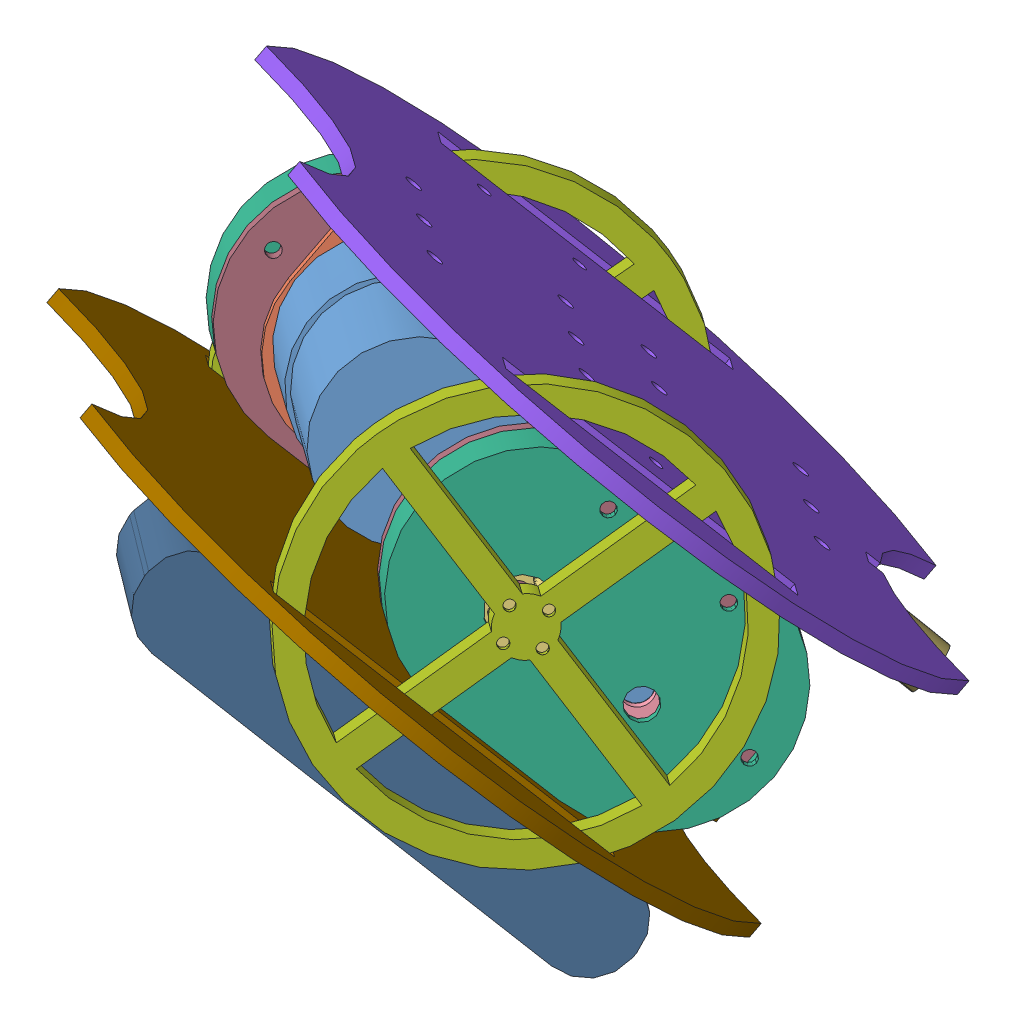
SolidWorks assembly prototype, configuration Default. Lengths in mm.
Overall size (210.36 170.64 188.11).
21 component instances, 13 part files, 47 mates.
Components (placement in the parent):
- 37D_30_1 motor-1: 37D_30_1 motor [Default] at (-25.5159 12.5017 82.0874) x (-0.250703 -0.71331 0.654474) z (-0.732412 -0.302323 -0.61006) size (36.8 36.8 74)
- 37D_30_1 motor-2: 37D_30_1 motor [Default] at (3.8647 -19.5138 58.4483) x (-0.250703 -0.71331 0.654474) z (0.732412 0.302323 0.61006) size (36.8 36.8 74)
- bracket-1: bracket [Default] at (7.9075 -5.1606 43.8592) x (-0.732412 -0.302323 -0.61006) z (-0.633025 0.632288 0.446644) size (51.2 41.6 37.6)
- bracket-3: bracket [Default] at (-19.1295 27.8223 69.4505) x (0.732412 0.302323 0.61006) z (0.633025 -0.632288 -0.446644) size (51.2 41.6 37.6)
- mod1.25_15_5mm_gear-1: mod1.25_15_5mm_gear [Default] at (28.8746 16.727 85.9165) x (0.398294 0.53646 -0.744025) z (0.732412 0.302323 0.61006) size (21.18 21.07 17)
- mod1.25_24_gear-1: mod1.25_24_gear [Default] at (22.8765 5.1631 98.8482) x (-0.593638 0.722326 0.354738) z (0.732412 0.302323 0.61006) size (32.31 32.31 2)
- 6mm_mounting_hub-1: 6mm_mounting_hub [Default] at (34.336 -11.2047 89.8723) x (0.651002 -0.048512 -0.757525) z (-0.199422 0.95197 -0.232344) size (25.4 9.2 25.4)
- 6mm_mounting_hub-2: 6mm_mounting_hub [Default] at (-59.497 -5.7937 59.8261) x (-0.524957 -0.319845 0.788745) z (-0.433581 0.897942 0.075552) size (25.4 9.2 25.4)
- gearbox_ver5-3: gearbox_ver5 [Default] at (32.0911 -0.6914 100.4708) x (-0.633025 0.632288 0.446644) z (0.732412 0.302323 0.61006) size (72.7 48 10)
- gearbox_ver5-4: gearbox_ver5 [Default] at (-57.2522 -16.307 49.2276) x (0.633025 -0.632288 -0.446644) z (-0.732412 -0.302323 -0.61006) size (72.7 48 10)
- wheel-1: wheel [Default] at (28.2216 8.343 108.8352) x (-0.552209 0.787916 0.272496) z (0.732412 0.302323 0.61006) size (80 80 5.3)
- mod1.25_15_5mm_gear-2: mod1.25_15_5mm_gear [Default] at (-33.4809 -39.4393 41.9363) x (0.544162 -0.79845 -0.257616) z (-0.732412 -0.302323 -0.61006) size (21.18 21.07 17)
- mod1.25_24_gear-2: mod1.25_24_gear [Default] at (-48.6213 2.3697 42.7749) x (0.497614 0.373868 -0.78269) z (0.732412 0.302323 0.61006) size (32.31 32.31 2)
- wheel-2: wheel [Default] at (-57.2644 -26.9437 37.6299) x (0.409219 0.520652 -0.749307) z (0.732412 0.302323 0.61006) size (80 80 5.3)
- base-2: base [Default] at (-4.8839 13.3994 54.7569) x (-0.633025 0.632288 0.446644) z (0.732412 0.302323 0.61006) size (137.46 2.9 150)
- base_2ndfloor-2: base_2ndfloor [Default] at (-17.6447 -22.9081 88.0696) x (-0.633025 0.632288 0.446644) z (0.732412 0.302323 0.61006) size (137.46 2.9 150)
- 11vbattery-1: 11vbattery [Default] at (7.0552 -15.4137 110.1303) x (-0.64782 0.625996 0.434118) z (0.719359 0.315147 0.619036) size (100 19 33)
- 7.4vbattery-1: 7.4vbattery [Default] at (-41.6591 -48.1627 75.64) x (0.647014 -0.626348 -0.434811) z (0.250703 0.71331 -0.654474) size (74 35 13)
- 1inch_spring-1: 1inch_spring [Default] at (38.6633 -36.2378 28.9452) x (-0.589271 -0.789928 0.169627) z (-0.69572 0.602861 0.390555) size (9.53 9.53 25.4)
- gearbox_top-1: gearbox_top [Default] at (24.1811 -3.9565 93.8822) x (-0.633025 0.632288 0.446644) z (0.732412 0.302323 0.61006) size (72.7 48 2.8)
- gearbox_top-2: gearbox_top [Default] at (-49.3421 -13.0419 55.8162) x (0.633025 -0.632288 -0.446644) z (-0.732412 -0.302323 -0.61006) size (72.7 48 2.8)
Mates (geometry in assembly coordinates):
- Coincident4: coincident anti-aligned: plane of 37D_30_1 motor-1 through (-41.629 5.8506 68.6661) normal (-0.732412 -0.302323 -0.61006); plane of bracket-3 through (-58.7445 2.9008 90.6761) normal (0.732412 0.302323 0.61006)
- Concentric6: concentric aligned: cylinder of 37D_30_1 motor-1 through (-41.1113 4.8037 88.2336) axis (-0.732412 -0.302323 -0.61006) radius 1.7; cylinder of bracket-3 through (-13.8648 16.0504 110.9284) axis (-0.732412 -0.302323 -0.61006) radius 1.65
- Concentric7: concentric aligned: cylinder of 37D_30_1 motor-1 through (-31.2994 -4.9968 81.3106) axis (-0.732412 -0.302323 -0.61006) radius 1.7; cylinder of bracket-3 through (-4.0529 6.2499 104.0054) axis (-0.732412 -0.302323 -0.61006) radius 1.65
- Coincident5: coincident anti-aligned: plane of 37D_30_1 motor-2 through (19.9778 -12.8627 71.8697) normal (0.732412 0.302323 0.61006); plane of bracket-1 through (26.6641 -39.5865 77.0858) normal (-0.732412 -0.302323 -0.61006)
- Concentric8: concentric aligned: cylinder of 37D_30_1 motor-2 through (12.7295 -30.9658 69.8727) axis (0.732412 0.302323 0.61006) radius 1.7; cylinder of bracket-1 through (-14.5169 -42.2126 47.1779) axis (0.732412 0.302323 0.61006) radius 1.65
- Concentric9: concentric aligned: cylinder of 37D_30_1 motor-2 through (2.9176 -21.1654 76.7957) axis (0.732412 0.302323 0.61006) radius 1.7; circle of bracket-1
- Coincident8: coincident aligned: plane of 37D_30_1 motor-2 through (36.0909 -6.2115 85.291) normal (0.732412 0.302323 0.61006); plane of 6mm_mounting_hub-1 through (34.336 -11.2047 89.8723) normal (0.732412 0.302323 0.61006)
- Concentric15: concentric aligned: cylinder of 37D_30_1 motor-2 through (25.547 -14.8326 82.5516) axis (-0.732412 -0.302323 -0.61006) radius 3; cylinder of 6mm_mounting_hub-1 through (34.336 -11.2047 89.8723) axis (-0.732412 -0.302323 -0.61006) radius 3
- Coincident9: coincident aligned: plane of 37D_30_1 motor-1 through (-57.7421 -0.8005 55.2448) normal (-0.732412 -0.302323 -0.61006); plane of 6mm_mounting_hub-2 through (-59.497 -5.7937 59.8261) normal (-0.732412 -0.302323 -0.61006)
- Concentric16: concentric aligned: cylinder of 37D_30_1 motor-1 through (-50.7081 -2.1658 67.1468) axis (0.732412 0.302323 0.61006) radius 3; cylinder of 6mm_mounting_hub-2 through (-59.497 -5.7937 59.8261) axis (0.732412 0.302323 0.61006) radius 3
- Coincident10: coincident anti-aligned: plane of mod1.25_24_gear-1 through (34.336 -11.2047 89.8723) normal (-0.732412 -0.302323 -0.61006); plane of 6mm_mounting_hub-1 through (34.336 -11.2047 89.8723) normal (0.732412 0.302323 0.61006)
- Coincident11: coincident anti-aligned: circle of 37D_30_1 motor-2; cylinder of mod1.25_24_gear-1 through (70.9566 3.9115 120.3753) axis (-0.732412 -0.302323 -0.61006) radius 3
- Coincident12: coincident aligned: plane of mod1.25_15_5mm_gear-1 through (18.7002 4.4128 100.9044) normal (-0.732412 -0.302323 -0.61006); plane of mod1.25_24_gear-1 through (34.336 -11.2047 89.8723) normal (-0.732412 -0.302323 -0.61006)
- Concentric26: concentric anti-aligned: cylinder of mod1.25_15_5mm_gear-1 through (55.3209 19.529 131.4074) axis (-0.732412 -0.302323 -0.61006) radius 2.5; cylinder of gearbox_ver5-3 through (24.5595 6.8314 105.7849) axis (0.732412 0.302323 0.61006) radius 6
- GearMate1: gear = 24 : 15 mm: cylinder of mod1.25_15_5mm_gear-1 through (55.3209 19.529 131.4074) axis (-0.732412 -0.302323 -0.61006) radius 2.5; cylinder of mod1.25_24_gear-1 through (70.9566 3.9115 120.3753) axis (-0.732412 -0.302323 -0.61006) radius 3
- Concentric27: concentric aligned: circle of mod1.25_15_5mm_gear-1; circle of wheel-1
- Concentric28: concentric aligned: cylinder of mod1.25_15_5mm_gear-1 through (33.6086 6.0461 110.0628) axis (-0.732412 -0.302323 -0.61006) radius 1.05; cylinder of wheel-1 through (34.5607 6.4391 110.8559) axis (-0.732412 -0.302323 -0.61006) radius 1.05
- Concentric29: concentric aligned: cylinder of mod1.25_15_5mm_gear-1 through (29.3789 7.1651 114.5863) axis (-0.732412 -0.302323 -0.61006) radius 1.05; cylinder of wheel-1 through (30.331 7.5581 115.3794) axis (-0.732412 -0.302323 -0.61006) radius 1.05
- Concentric30: concentric anti-aligned: cylinder of 6mm_mounting_hub-2 through (-59.497 -5.7937 59.8261) axis (0.732412 0.302323 0.61006) radius 3; cylinder of mod1.25_24_gear-2 through (-24.3412 8.7179 89.109) axis (-0.732412 -0.302323 -0.61006) radius 3
- Coincident18: coincident anti-aligned: plane of 6mm_mounting_hub-2 through (-59.497 -5.7937 59.8261) normal (-0.732412 -0.302323 -0.61006); plane of mod1.25_24_gear-2 through (-59.497 -5.7937 59.8261) normal (0.732412 0.302323 0.61006)
- Coincident19: coincident aligned: plane of mod1.25_15_5mm_gear-2 through (-43.8613 -21.4112 48.794) normal (0.732412 0.302323 0.61006); plane of mod1.25_24_gear-2 through (-59.497 -5.7937 59.8261) normal (0.732412 0.302323 0.61006)
- Concentric31: concentric anti-aligned: cylinder of gearbox_ver5-4 through (-49.7206 -23.8298 43.9135) axis (-0.732412 -0.302323 -0.61006) radius 6; cylinder of mod1.25_15_5mm_gear-2 through (-80.4819 -36.5274 18.291) axis (0.732412 0.302323 0.61006) radius 2.5
- Concentric32: concentric anti-aligned: cylinder of mod1.25_15_5mm_gear-2 through (-58.1333 -28.8676 41.7574) axis (0.732412 0.302323 0.61006) radius 1.05; cylinder of wheel-2 through (-55.2037 -27.6583 44.1977) axis (-0.732412 -0.302323 -0.61006) radius 1.05
- Concentric33: concentric anti-aligned: cylinder of mod1.25_15_5mm_gear-2 through (-53.8908 -30.1038 37.2766) axis (0.732412 0.302323 0.61006) radius 1.05; cylinder of wheel-2 through (-50.9611 -28.8945 39.7169) axis (-0.732412 -0.302323 -0.61006) radius 1.05
- GearMate2: gear = 24 : 15 mm: cylinder of mod1.25_15_5mm_gear-2 through (-80.4819 -36.5274 18.291) axis (0.732412 0.302323 0.61006) radius 2.5; cylinder of mod1.25_24_gear-2 through (-24.3412 8.7179 89.109) axis (-0.732412 -0.302323 -0.61006) radius 3
- Concentric34: concentric anti-aligned: cylinder of gearbox_ver5-3 through (30.5809 -22.7856 106.6763) axis (0.250703 0.71331 -0.654474) radius 1.4; cylinder of base-2 through (45.1216 18.5864 68.7168) axis (-0.250703 -0.71331 0.654474) radius 1.4
- Concentric35: concentric anti-aligned: cylinder of gearbox_ver5-3 through (18.1862 -10.4054 115.4216) axis (0.250703 0.71331 -0.654474) radius 1.4; cylinder of base-2 through (32.727 30.9666 77.4621) axis (-0.250703 -0.71331 0.654474) radius 1.4
- Coincident21: coincident anti-aligned: plane of gearbox_ver5-3 through (33.2014 16.72 77.396) normal (0.250703 0.71331 -0.654474); plane of base-2 through (-5.611 11.3308 56.6548) normal (-0.250703 -0.71331 0.654474)
- Coincident22: coincident anti-aligned: plane of wheel-1 through (28.2216 8.343 108.8352) normal (-0.732412 -0.302323 -0.61006); plane of base-2 through (37.6982 35.3061 84.0961) normal (0.732412 0.302323 0.61006)
- Coincident23: coincident anti-aligned: plane of bracket-1 through (7.9075 -5.1606 43.8592) normal (0.250703 0.71331 -0.654474); plane of base-2 through (-5.611 11.3308 56.6548) normal (-0.250703 -0.71331 0.654474)
- Concentric37: concentric anti-aligned: cylinder of bracket-3 through (-13.9789 42.6686 90.6603) axis (0.250703 0.71331 -0.654474) radius 1.6; cylinder of base-2 through (-10.9705 51.2284 82.8066) axis (-0.250703 -0.71331 0.654474) radius 1.6
- Coincident24: coincident anti-aligned: plane of bracket-3 through (-19.1295 27.8223 69.4505) normal (0.250703 0.71331 -0.654474); plane of base-2 through (-5.611 11.3308 56.6548) normal (-0.250703 -0.71331 0.654474)
- Concentric38: concentric anti-aligned: cylinder of bracket-1 through (10.1284 8.4764 62.6288) axis (0.250703 0.71331 -0.654474) radius 1.6; cylinder of base-2 through (13.1368 17.0361 54.7751) axis (-0.250703 -0.71331 0.654474) radius 1.6
- Coincident25: coincident anti-aligned: plane of gearbox_ver5-4 through (-44.4233 5.9416 35.9137) normal (0.250703 0.71331 -0.654474); plane of base-2 through (-5.611 11.3308 56.6548) normal (-0.250703 -0.71331 0.654474)
- Concentric39: concentric anti-aligned: cylinder of gearbox_ver5-4 through (-65.8703 -23.0305 69.4629) axis (0.250703 0.71331 -0.654474) radius 1.4; cylinder of base-2 through (-51.3295 18.3415 31.5034) axis (-0.250703 -0.71331 0.654474) radius 1.4
- Coincident26: coincident anti-aligned: plane of wheel-2 through (-53.3827 -25.3414 40.8632) normal (0.732412 0.302323 0.61006); plane of base-2 through (-43.9061 1.6217 16.1241) normal (-0.732412 -0.302323 -0.61006)
- Coincident27: coincident anti-aligned: plane of gearbox_ver5-3 through (21.1676 -17.5189 108.8107) normal (-0.250703 -0.71331 0.654474); plane of base_2ndfloor-2 through (-17.6447 -22.9081 88.0696) normal (0.250703 0.71331 -0.654474)
- Concentric40: concentric anti-aligned: cylinder of gearbox_ver5-3 through (18.1862 -10.4054 115.4216) axis (0.250703 0.71331 -0.654474) radius 1.4; cylinder of base_2ndfloor-2 through (19.9662 -5.3409 110.7748) axis (-0.250703 -0.71331 0.654474) radius 1.4
- Concentric41: concentric anti-aligned: cylinder of gearbox_ver5-3 through (30.5809 -22.7856 106.6763) axis (0.250703 0.71331 -0.654474) radius 1.4; cylinder of base_2ndfloor-2 through (32.3609 -17.7211 102.0295) axis (-0.250703 -0.71331 0.654474) radius 1.4
- Coincident30: coincident anti-aligned: plane of base_2ndfloor-2 through (-18.3718 -24.9767 89.9676) normal (-0.250703 -0.71331 0.654474); plane of 11vbattery-1 through (7.0552 -15.4137 110.1303) normal (0.250703 0.71331 -0.654474)
- Coincident31: coincident anti-aligned: plane of base_2ndfloor-2 through (-18.3718 -24.9767 89.9676) normal (-0.250703 -0.71331 0.654474); plane of 7.4vbattery-1 through (-38.4 -38.8897 67.1318) normal (0.250703 0.71331 -0.654474)
- Coincident32: coincident anti-aligned: plane of gearbox_ver5-3 through (26.2318 -3.11 95.5903) normal (-0.732412 -0.302323 -0.61006); plane of gearbox_top-1 through (26.2318 -3.11 95.5903) normal (0.732412 0.302323 0.61006)
- Coincident33: coincident anti-aligned: plane of base-2 through (-5.611 11.3308 56.6548) normal (-0.250703 -0.71331 0.654474); plane of gearbox_top-1 through (33.2014 16.72 77.396) normal (0.250703 0.71331 -0.654474)
- Concentric42: concentric anti-aligned: cylinder of gearbox_ver5-3 through (35.2886 -8.4941 87.3853) axis (0.732412 0.302323 0.61006) radius 24; cylinder of gearbox_top-1 through (35.2886 -8.4941 87.3853) axis (-0.732412 -0.302323 -0.61006) radius 24
- Coincident34: coincident anti-aligned: plane of gearbox_ver5-4 through (-51.3929 -13.8884 54.1081) normal (0.732412 0.302323 0.61006); plane of gearbox_top-2 through (-51.3929 -13.8884 54.1081) normal (-0.732412 -0.302323 -0.61006)
- Coincident35: coincident anti-aligned: plane of base-2 through (-5.611 11.3308 56.6548) normal (-0.250703 -0.71331 0.654474); plane of gearbox_top-2 through (-44.4233 5.9416 35.9137) normal (0.250703 0.71331 -0.654474)
- Concentric43: concentric anti-aligned: cylinder of gearbox_ver5-4 through (-42.9086 -18.7006 46.307) axis (-0.732412 -0.302323 -0.61006) radius 24; cylinder of gearbox_top-2 through (-42.9086 -18.7006 46.307) axis (0.732412 0.302323 0.61006) radius 24
